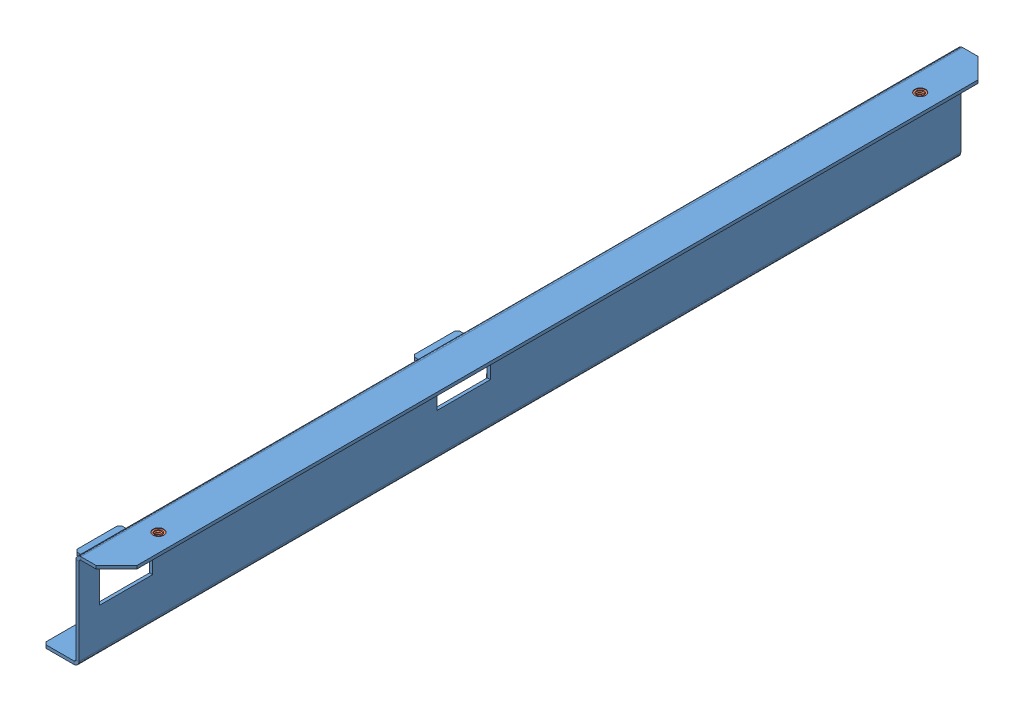
SolidWorks assembly OB_1735314-C_1U-Inner-Bracket, configuration Default. Lengths in mm.
Overall size (28.75 38.1 346.96).
3 component instances, 2 part files, 5 mates.
Components (placement in the parent):
- OB_1735314-C_1U-Inner-Bracket-1: OB_1735314-C_1U-Inner-Bracket [Default] at origin size (28.75 38.1 346.96)
- S-440-1ZI_SELF-CLINCHING-NUT-1: S-440-1ZI_SELF-CLINCHING-NUT [95185A120] at (8.89 35.1028 149.86) x (1 0 0) z (0 -1 0) size (6.35 6.35 3.2)
- S-440-1ZI_SELF-CLINCHING-NUT-2: S-440-1ZI_SELF-CLINCHING-NUT [95185A120] at (8.89 35.1028 -149.86) x (1 0 0) z (0 -1 0) size (6.35 6.35 3.2)
Mates (geometry in assembly coordinates):
- Concentric5: concentric aligned: cylinder of OB_1735314-C_1U-Inner-Bracket-1 through (8.89 38.1 149.86) axis (0 -1 0) radius 2.1082; circle of S-440-1ZI_SELF-CLINCHING-NUT-1
- Coincident86: coincident anti-aligned: plane of OB_1735314-C_1U-Inner-Bracket-1 through (16 36.8808 173.482) normal (0 -1 0); plane of S-440-1ZI_SELF-CLINCHING-NUT-1 through (8.89 36.8808 149.86) normal (0 1 0)
- Coincident87: coincident aligned: plane of OB_1735314-C_1U-Inner-Bracket-1 through (0 0 0) normal (0 0 1); plane of assembly through (0 0 0) normal (0 0 1)
- Coincident88: coincident aligned: plane of OB_1735314-C_1U-Inner-Bracket-1 through (0 0 0) normal (0 1 0); plane of assembly through (0 0 0) normal (0 1 0)
- Coincident89: coincident aligned: plane of OB_1735314-C_1U-Inner-Bracket-1 through (0 0 0) normal (1 0 0); plane of assembly through (0 0 0) normal (1 0 0)
